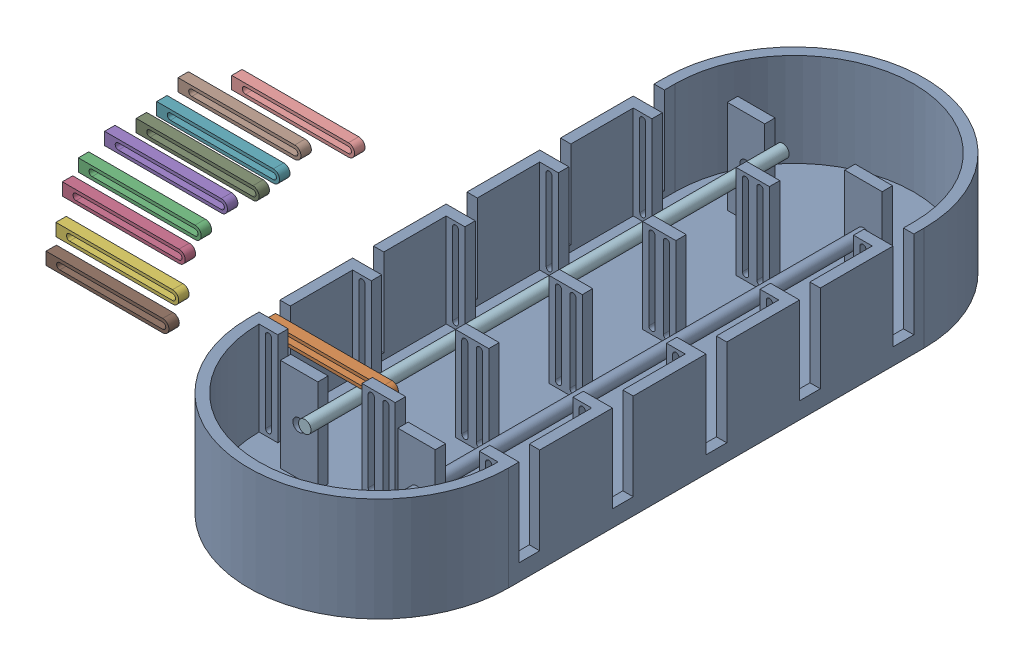
SolidWorks assembly V2 Assm, configuration Default. Lengths in mm.
Overall size (209.97 120.01 325).
13 component instances, 3 part files, 5 mates.
Components (placement in the parent):
- Body-1: Body [Default] at origin size (125 50 325)
- Arm-1: Arm [Default] at (-52.9909 45.3923 -10) size (59.12 6 5)
- Arm-2: Arm [Default] at (-138.4299 72.1702 -5.5971) size (59.12 6 5)
- Arm-3: Arm [Default] at (-140.8558 63.6076 -0.3215) size (59.12 6 5)
- Arm-4: Arm [Default] at (-132.254 83.0867 -12.0471) size (59.12 6 5)
- Arm-5: Arm [Default] at (-137.166 51.9684 6.4891) size (59.12 6 5)
- Arm-6: Arm [Default] at (-116.1683 99.0541 -21.0174) size (59.12 6 5)
- Arm-7: Arm [Default] at (-111.5657 108.4375 -26.7025) size (59.12 6 5)
- Arm-8: Arm [Default] at (-121.3721 91.7401 -16.3649) size (59.12 6 5)
- Arm-9: Arm [Default] at (-91.0326 117.0127 -31.9843) size (59.12 6 5)
- Arm-10: Arm [Default] at (-136.455 43.058 11.9382) size (59.12 6 5)
- Axel-1: Axel [Default] at (-15.5088 38.226 -210) size (6 6 230)
- Axel-2: Axel [Default] at (28.25 27.5 -210) size (6 6 230)
Mates (geometry in assembly coordinates):
- Coincident1: coordinate: point of Body-1
- Coincident2: coincident anti-aligned: plane of Body-1 through (0 50 -5) normal (0 0 -1); plane of Arm-1 through (-3.4909 45.3923 -5) normal (0 0 1)
- Coincident3: coincident anti-aligned: plane of Body-1 through (0 50 -5) normal (0 0 -1); plane of Arm-1 through (-3.4909 45.3923 -5) normal (0 0 1)
- Coincident14: coincident aligned: plane of Body-1 through (-37.25 50 -210) normal (0 0 -1); plane of Axel-1 through (-15.5088 38.226 -210) normal (0 0 -1)
- Coincident17: coincident anti-aligned: plane of Body-1 through (19.25 50 -210) normal (0 0 -1); circle of Axel-2
